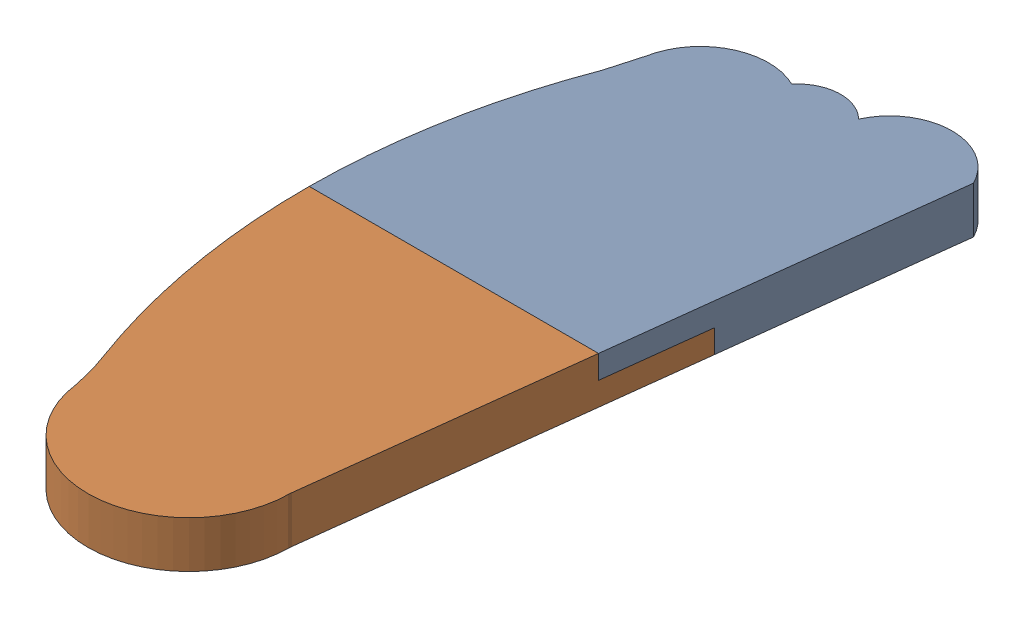
SolidWorks assembly left_foot, configuration Défaut. Lengths in mm.
Overall size (95.34 13.5 216.03).
2 component instances, 2 part files, 3 mates.
Components (placement in the parent):
- left_forefoot-1: left_forefoot [Défaut] at (-232.9785 119.4896 3.2786) size (95.34 13.5 106.98)
- left_backfoot-1: left_backfoot [Défaut] at (-232.9785 119.4896 3.2786) size (87.34 13.5 139.05)
Mates (geometry in assembly coordinates):
- Coïncidente1: coincident: point of left_forefoot-1; point of left_backfoot-1
- Coïncidente2: coincident: point of left_forefoot-1; point of left_backfoot-1
- Coïncidente3: coincident: point of left_forefoot-1; point of left_backfoot-1
